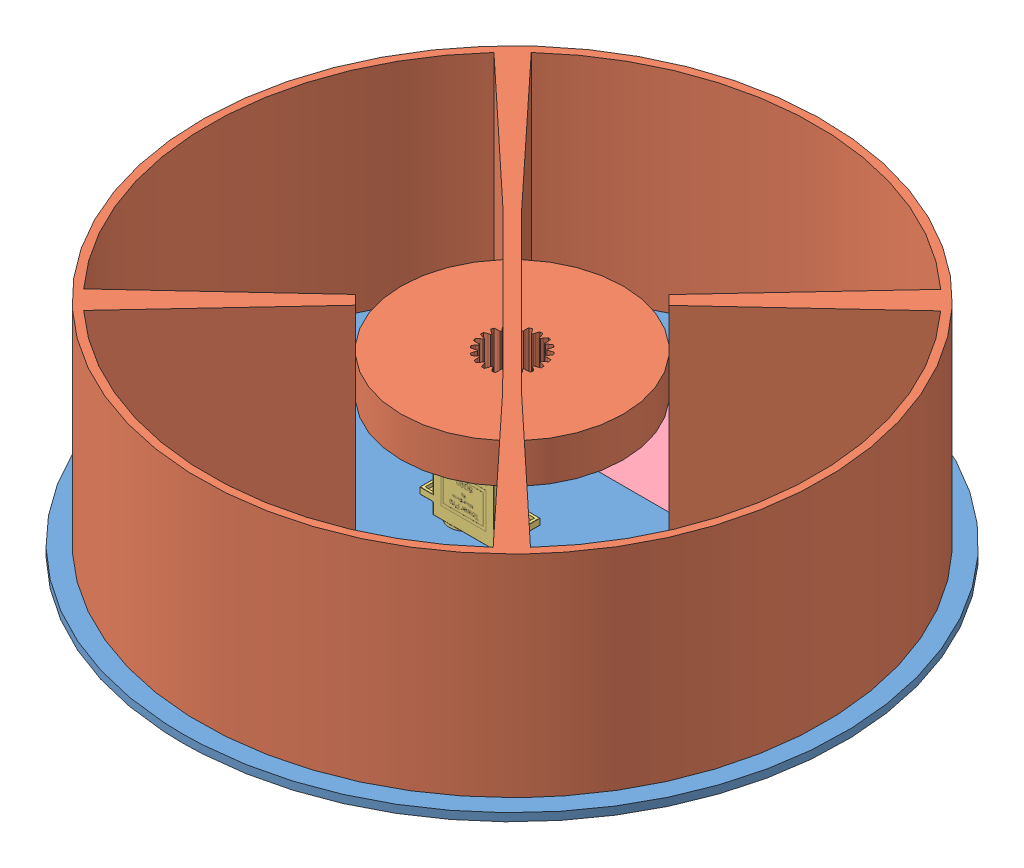
SolidWorks assembly Top Bırakma Tepsisi, configuration Varsayılan. Lengths in mm.
Overall size (333.57 90 333.57).
5 component instances, 5 part files, 11 mates.
Components (placement in the parent):
- Alt Tabla-1: Alt Tabla [Varsayılan] at (-5.2891 -4.5514 50) size (250 10 250)
- silindir kabuk-1: silindir kabuk [Varsayılan] at (-5.2891 78.4486 50) x (0.730332 0 0.683093) z (0.683093 0 -0.730332) size (236 80 236)
- TP SG90-1: TP SG90 [Varsayılan] at (-17.1577 22.0486 50.3838) x (0 0 -1) z (-1 0 0) size (12.64 29.82 33.01)
- Alt Kapak-1: Alt Kapak [Varsayılan] at (-1.4063 -7.5514 -20.383) x (1 0 0) z (0 1 0) size (72.76 118.95 3)
- low pinion-1: low pinion [Varsayılan] at (-22.4077 -4.5514 50.3838) x (0.394328 0 -0.91897) z (-0.91897 0 -0.394328) size (5.46 3 5.46)
Mates (geometry in assembly coordinates):
- Çakışık26: coincident anti-aligned: plane of Alt Tabla-1 through (-5.2891 -1.5514 50) normal (0 1 0); plane of silindir kabuk-1 through (-5.2891 -1.5514 50) normal (0 -1 0)
- Paralel12: parallel aligned: plane of Alt Tabla-1 through (-5.2891 -1.5514 10) normal (0 0 -1); plane of TP SG90-1 through (-17.1577 10.7986 44.1338) normal (0 0 -1)
- Çakışık36: coincident anti-aligned: plane of Alt Tabla-1 through (-5.2891 -4.5514 50) normal (0 -1 0); plane of Alt Kapak-1 through (-1.4063 -4.5514 -20.383) normal (0 1 0)
- Eş Merkezli13: concentric anti-aligned: cylinder of TP SG90-1 through (-22.4077 -0.4514 50.3838) axis (0 -1 0) radius 6.25; cylinder of low pinion-1 through (-22.4077 -7.5514 50.3838) axis (0 1 0) radius 1
- Çakışık40: coincident anti-aligned: plane of TP SG90-1 through (-21.7202 -4.5514 50.3838) normal (0 -1 0); plane of low pinion-1 through (-22.4077 -4.5514 50.3838) normal (0 1 0)
- Çakışık41: coincident aligned: plane of Alt Tabla-1 through (-5.2891 -4.5514 50) normal (0 -1 0); plane of TP SG90-1 through (-21.7202 -4.5514 50.3838) normal (0 -1 0)
- Eş Merkezli17: concentric aligned: cylinder of Alt Tabla-1 through (-22.4077 -1.5514 50.3838) axis (0 -1 0) radius 6.15; cylinder of TP SG90-1 through (-22.4077 -0.4514 50.3838) axis (0 -1 0) radius 6.25
- Eş Merkezli18: concentric anti-aligned: cylinder of Alt Kapak-1 through (-22.4077 -4.5514 50.3838) axis (0 -1 0) radius 2.85; cylinder of low pinion-1 through (-22.4077 -7.5514 50.3838) axis (0 1 0) radius 2.75
- Eş Merkezli19: concentric anti-aligned: cylinder of Alt Tabla-1 through (-5.2891 -1.5514 50) axis (0 -1 0) radius 125; cylinder of silindir kabuk-1 through (-5.2891 -1.5514 50) axis (0 1 0) radius 118
- Slot1: slot aligned: cylinder of Alt Kapak-1 through (-22.4077 -7.5514 50.3838) axis (0 1 0) radius 18.83; cylinder of Alt Tabla-1 through (-0.9705 -7.5514 47.8974) axis (0 1 0) radius 2.5; cylinder of Alt Kapak-1 through (-0.8277 -7.5514 50.3838) axis (0 1 0) radius 2.75
- LimitAngle1: limit planar angle = 0 rad anti-aligned: plane of Alt Tabla-1 through (-43.2891 -8.5514 50) normal (1 0 0); plane of Alt Kapak-1 through (-43.2267 -4.5514 -20.383) normal (-1 0 0)
